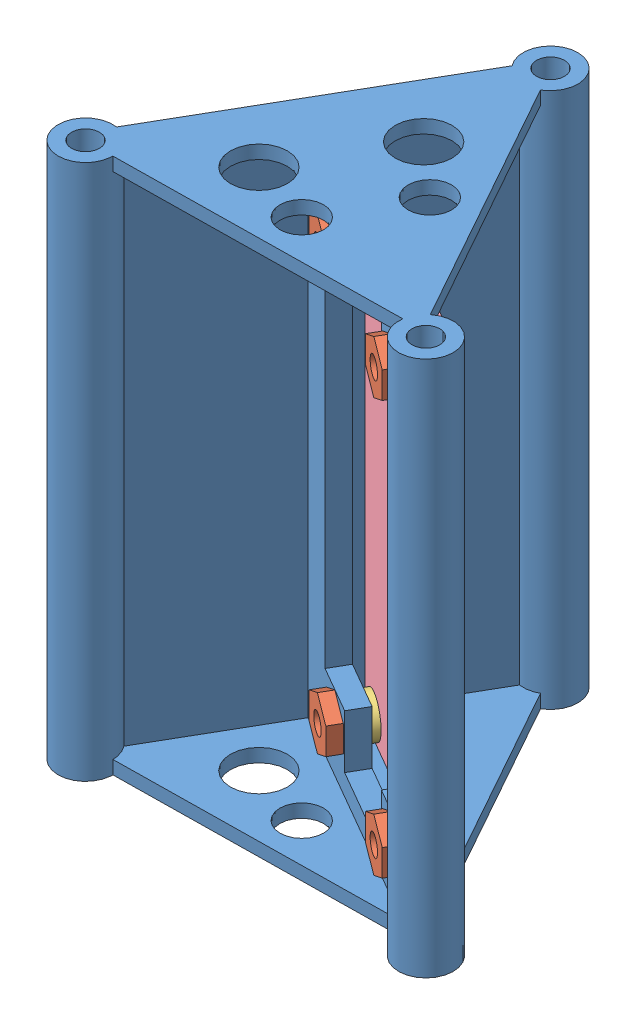
SolidWorks assembly Sensor_Stack_Assy, configuration Default. Lengths in mm.
Overall size (58.99 80 52.18).
10 component instances, 4 part files, 19 mates.
Components (placement in the parent):
- Sensor_Stack_T_Mount_A2-1: Sensor_Stack_T_Mount_A2 [Default] at (9.5389 -1.0891 74.5991) size (58.99 80 52.18)
- 6.86mm_Nut_3mm_Hole-1: 6.86mm_Nut_3mm_Hole [Default] at (6.8862 79.7859 74.7996) x (0.75 0.5 0.433013) z (0.433013 -0.866025 0.25) size (7.92 1.91 6.86)
- Ruber_Washer_3mm-1: Ruber_Washer_3mm [Default] at (28.3048 79.7859 83.7015) x (0.75 -0.5 0.433013) z (0.433013 0.866025 0.25) size (6 1.25 6)
- Ruber_Washer_3mm-2: Ruber_Washer_3mm [Default] at (8.3862 79.7859 72.2015) x (0.75 -0.5 0.433013) z (0.433013 0.866025 0.25) size (6 1.25 6)
- Ruber_Washer_3mm-3: Ruber_Washer_3mm [Default] at (28.3048 18.0359 83.7015) x (0.75 -0.5 0.433013) z (0.433013 0.866025 0.25) size (6 1.25 6)
- Ruber_Washer_3mm-4: Ruber_Washer_3mm [Default] at (8.3862 18.0359 72.2015) x (0.75 -0.5 0.433013) z (0.433013 0.866025 0.25) size (6 1.25 6)
- 6.86mm_Nut_3mm_Hole-3: 6.86mm_Nut_3mm_Hole [Default] at (26.8048 18.0359 86.2996) x (0.75 0.5 0.433013) z (0.433013 -0.866025 0.25) size (7.92 1.91 6.86)
- 6.86mm_Nut_3mm_Hole-4: 6.86mm_Nut_3mm_Hole [Default] at (6.8862 18.0359 74.7996) x (0.75 0.5 0.433013) z (0.433013 -0.866025 0.25) size (7.92 1.91 6.86)
- 6.86mm_Nut_3mm_Hole-2: 6.86mm_Nut_3mm_Hole [Default] at (26.8048 79.7859 86.2996) x (0.75 0.5 0.433013) z (0.433013 -0.866025 0.25) size (7.92 1.91 6.86)
- Sensor_PCB-1: Sensor_PCB [Default] at (32.9609 14.7859 82.637) x (0 1 0) z (0.866025 0 0.5) size (68.25 2 30)
Mates (geometry in assembly coordinates):
- Coincident1: coincident aligned: plane of Ruber_Washer_3mm-1 through (28.3048 79.7859 83.7015) normal (-0.5 0 0.866025); plane of Ruber_Washer_3mm-2 through (8.3862 79.7859 72.2015) normal (-0.5 0 0.866025)
- Coincident2: coincident aligned: plane of Ruber_Washer_3mm-1 through (28.3048 79.7859 83.7015) normal (-0.5 0 0.866025); plane of Ruber_Washer_3mm-4 through (8.3862 18.0359 72.2015) normal (-0.5 0 0.866025)
- Coincident3: coincident aligned: plane of Ruber_Washer_3mm-3 through (28.3048 18.0359 83.7015) normal (-0.5 0 0.866025); plane of Ruber_Washer_3mm-4 through (8.3862 18.0359 72.2015) normal (-0.5 0 0.866025)
- Coincident4: coincident anti-aligned: plane of Sensor_Stack_T_Mount_A2-1 through (10.2889 88.9109 73.3001) normal (0.5 0 -0.866025); plane of Ruber_Washer_3mm-2 through (8.3862 79.7859 72.2015) normal (-0.5 0 0.866025)
- Concentric1: concentric anti-aligned: circle of Sensor_Stack_T_Mount_A2-1; circle of Ruber_Washer_3mm-2
- Concentric2: concentric anti-aligned: circle of Sensor_Stack_T_Mount_A2-1; circle of Ruber_Washer_3mm-3
- Concentric3: concentric anti-aligned: circle of Sensor_Stack_T_Mount_A2-1; circle of Ruber_Washer_3mm-4
- Concentric4: concentric anti-aligned: circle of Sensor_Stack_T_Mount_A2-1; circle of Ruber_Washer_3mm-1
- Coincident5: coincident aligned: plane of 6.86mm_Nut_3mm_Hole-1 through (6.8862 79.7859 74.7996) normal (0.5 0 -0.866025); plane of 6.86mm_Nut_3mm_Hole-4 through (6.8862 18.0359 74.7996) normal (0.5 0 -0.866025)
- Coincident6: coincident aligned: plane of 6.86mm_Nut_3mm_Hole-1 through (6.8862 79.7859 74.7996) normal (0.5 0 -0.866025); plane of 6.86mm_Nut_3mm_Hole-2 through (26.8048 79.7859 86.2996) normal (0.5 0 -0.866025)
- Coincident7: coincident aligned: plane of 6.86mm_Nut_3mm_Hole-2 through (26.8048 79.7859 86.2996) normal (0.5 0 -0.866025); plane of 6.86mm_Nut_3mm_Hole-3 through (26.8048 18.0359 86.2996) normal (0.5 0 -0.866025)
- Coincident8: coincident anti-aligned: plane of Sensor_Stack_T_Mount_A2-1 through (8.7889 88.9109 75.8981) normal (-0.5 0 0.866025); plane of 6.86mm_Nut_3mm_Hole-4 through (6.8862 18.0359 74.7996) normal (0.5 0 -0.866025)
- Concentric5: concentric aligned: circle of Sensor_Stack_T_Mount_A2-1; circle of 6.86mm_Nut_3mm_Hole-4
- Concentric7: concentric aligned: circle of Sensor_Stack_T_Mount_A2-1; circle of 6.86mm_Nut_3mm_Hole-3
- Concentric8: concentric aligned: circle of Sensor_Stack_T_Mount_A2-1; circle of 6.86mm_Nut_3mm_Hole-2
- Concentric9: concentric aligned: circle of Sensor_Stack_T_Mount_A2-1; circle of 6.86mm_Nut_3mm_Hole-1
- Coincident9: coincident anti-aligned: plane of Ruber_Washer_3mm-4 through (9.0112 18.0359 71.119) normal (0.5 0 -0.866025); plane of Sensor_PCB-1 through (31.9609 14.7859 84.369) normal (-0.5 0 0.866025)
- Concentric10: concentric anti-aligned: circle of Ruber_Washer_3mm-2; circle of Sensor_PCB-1
- Concentric11: concentric aligned: cylinder of Sensor_Stack_T_Mount_A2-1 through (30.6029 18.0359 79.7211) axis (-0.5 0 0.866025) radius 1.625; circle of Sensor_PCB-1
